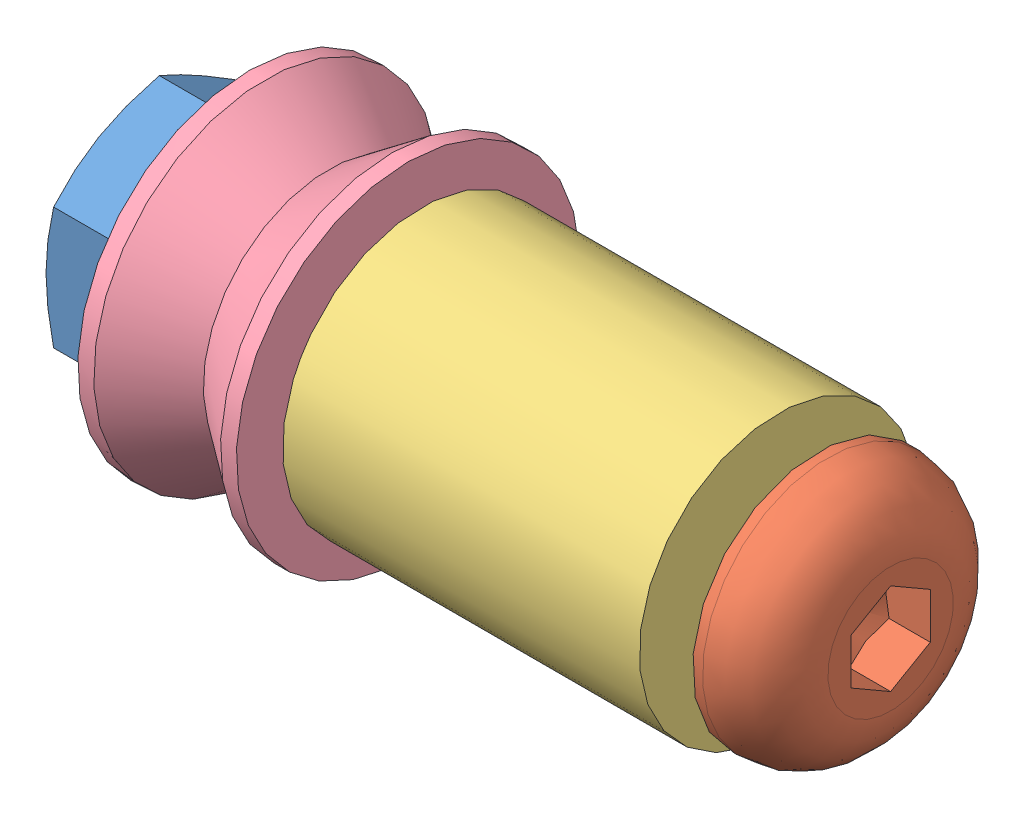
SolidWorks assembly PULLEY ASSEMBLY, configuration Long. Lengths in mm.
Overall size (27.97 16.9 16.9).
5 component instances, 5 part files, 9 mates.
Components (placement in the parent):
- 625vv-1: 625vv [Default] at origin (hidden)
- M5 NUT-1: M5 NUT [Default] at (-7.2 0 0) x (1 0 0) z (0 0.866025 0.5)
- M5X25-1: M5X25 [Default] at (18.0189 0 0) x (-1 0 0) z (0 0.5 -0.866025)
- PULLEY SPACER 1-1: PULLEY SPACER 1 [Long] at (2.5 0 0) x (0 -0.5 -0.866025) z (1 0 0) size (10.5 10.5 14)
- M4 V-groove pulley-1: M4 V-groove pulley [Default] at (2.5 0 0) x (0 0.92849 -0.371357) z (0 0.371357 0.92849)
Mates (geometry in assembly coordinates):
- Concentric1: concentric anti-aligned: cylinder of M5X25-1 through (4.7189 0 0) axis (-1 0 0) radius 2.5; cylinder of PULLEY SPACER 1-1 through (2.5 0 0) axis (1 0 0) radius 5.25
- Concentric2: concentric aligned: cone of 625vv-1 through (0.5 0 0) axis (-1 0 0); cylinder of M5X25-1 through (4.7189 0 0) axis (-1 0 0) radius 2.5
- Distance2: distance = 1.5189 mm anti-aligned: plane of M5X25-1 through (18.0189 3.1393 1.8125) normal (-1 0 0); plane of PULLEY SPACER 1-1 through (16.5 0 0) normal (1 0 0)
- Concentric3: concentric anti-aligned: cylinder of M5 NUT-1 through (-15.5929 0 0) axis (1 0 0) radius 2.067; cylinder of M5X25-1 through (4.7189 0 0) axis (-1 0 0) radius 2.5
- Coincident3: coincident anti-aligned: plane of 625vv-1 through (-2.5 5.25 0) normal (-1 0 0); plane of M5 NUT-1 through (-2.5 0 0) normal (1 0 0)
- Parallel1: parallel anti-aligned: plane of M5 NUT-1 through (-7.2 2.3094 -4) normal (0 0 -1); plane of assembly through (0 0 0) normal (0 0 1)
- Coincident4: coincident anti-aligned: plane of 625vv-1 through (2.5 5.25 0) normal (1 0 0); plane of PULLEY SPACER 1-1 through (2.5 -2.625 -4.5466) normal (-1 0 0)
- Concentric4: concentric aligned: cylinder of M5X25-1 through (4.7189 0 0) axis (-1 0 0) radius 2.5; cylinder of M4 V-groove pulley-1 through (2.501 0 0) axis (-1 0 0) radius 2.05
- Coincident5: coincident anti-aligned: plane of PULLEY SPACER 1-1 through (2.5 -2.625 -4.5466) normal (-1 0 0); plane of M4 V-groove pulley-1 through (2.5 6.0352 -2.4138) normal (1 0 0)
